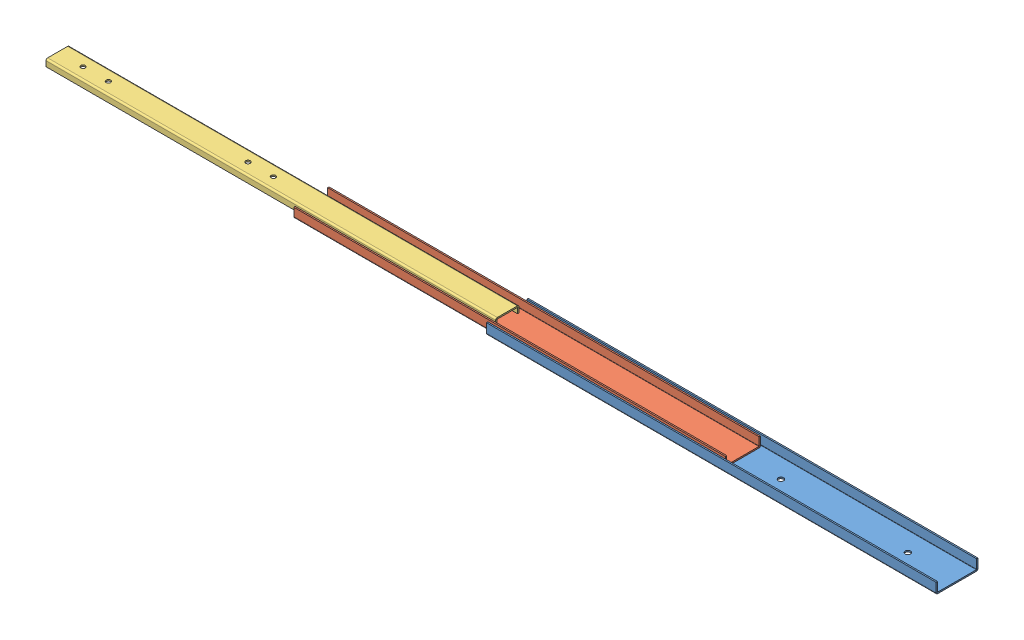
SolidWorks assembly basicSLider, configuration Default. Lengths in mm.
Overall size (900.05 11.05 42).
3 component instances, 3 part files, 8 mates.
Components (placement in the parent):
- slide3-1: slide3 [Default] at (-307.1643 -9.242 32.0307) size (450 10.75 42)
- slide2-1: slide2 [Default] at (-503.2259 -6.442 27.2807) size (431.8 9.65 35.3)
- slide1-1: slide1 [Default] at (-757.2156 0.658 -1.0943) x (1 0 0) z (0 0 -1) size (450 7.1 23.3)
Mates (geometry in assembly coordinates):
- Coincident1: coincident anti-aligned: plane of slide3-1 through (142.8357 -7.842 32.0307) normal (0 1 0); plane of slide2-1 through (-71.4259 -7.842 27.2807) normal (0 -1 0)
- Parallel1: parallel anti-aligned: plane of slide3-1 through (142.8357 -9.242 30.6307) normal (0 0 -1); plane of slide2-1 through (-71.4259 -6.442 28.6807) normal (0 0 1)
- Distance1: distance = 1.95 mm anti-aligned: plane of slide3-1 through (142.8357 -9.242 -8.5693) normal (0 0 1); plane of slide2-1 through (-71.4259 -6.442 -6.6193) normal (0 0 -1)
- LimitDistance1: limit distance = 214.2616 mm aligned: plane of slide2-1 through (-71.4259 -6.192 28.6807) normal (1 0 0); plane of slide3-1 through (142.8357 -7.592 -8.5693) normal (1 0 0)
- Coincident5: coincident anti-aligned: plane of slide2-1 through (-71.4259 -6.442 27.2807) normal (0 1 0); plane of slide1-1 through (-307.2156 -6.442 -0.6193) normal (0 -1 0)
- Distance3: distance = 4.6 mm anti-aligned: plane of slide2-1 through (-71.4259 -6.442 -5.2193) normal (0 0 1); plane of slide1-1 through (-307.2156 -0.942 -0.6193) normal (0 0 -1)
- LimitDistance3: limit distance = 450.0513 mm aligned: plane of slide1-1 through (-307.2156 0.458 21.0307) normal (1 0 0); plane of slide3-1 through (142.8357 -7.842 30.3807) normal (1 0 0)
- LimitDistance4: limit distance = 253.9898 mm aligned: plane of slide2-1 through (-503.2259 -6.192 27.2807) normal (-1 0 0); plane of slide1-1 through (-757.2156 -0.942 21.0307) normal (-1 0 0)
